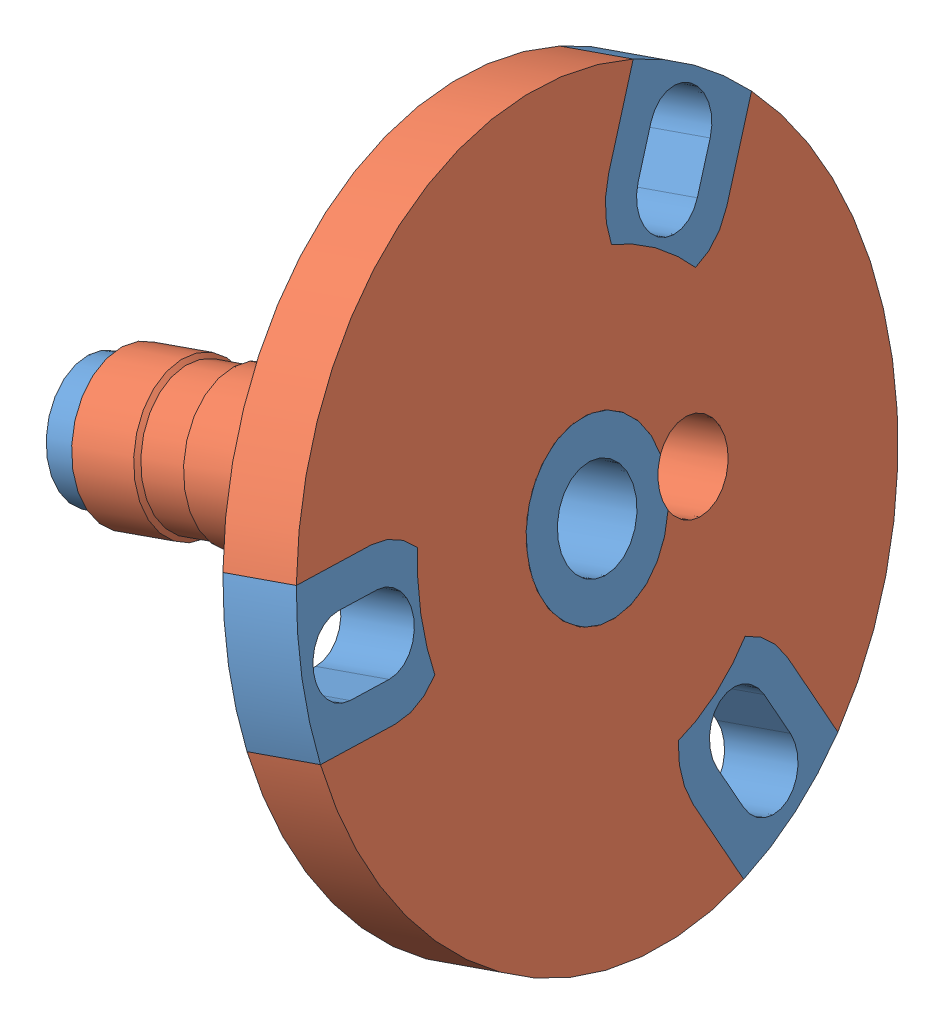
SolidWorks assembly Needle Holder Assembly, configuration Default. Lengths in mm.
Overall size (40.69 54.24 49.24).
2 component instances, 2 part files, 2 mates.
Components (placement in the parent):
- NeedleMountBottom_Heated_Rev3_Conductive-1: NeedleMountBottom_Heated_Rev3_Conductive [Default] at (-31.0476 22.1883 -11.3266) x (0.266536 -0.959645 0.089661) z (0.089661 0.11731 0.98904) size (41.78 27.15 36.24)
- NeedleMountBottom_Heated_Rev3_Standard-7: NeedleMountBottom_Heated_Rev3_Standard [Default] at (-31.0476 22.1883 -11.3266) x (0.266536 -0.959645 0.089661) z (0.089661 0.11731 0.98904) size (44.6 25.22 42.58)
Mates (geometry in assembly coordinates):
- Coincident5: coincident aligned: plane of NeedleMountBottom_Heated_Rev3_Conductive-1 through (-31.0476 22.1883 -11.3266) normal (0.959645 0.255576 -0.11731); plane of NeedleMountBottom_Heated_Rev3_Standard-7 through (-31.0476 22.1883 -11.3266) normal (0.959645 0.255576 -0.11731)
- Concentric1: concentric aligned: circle of NeedleMountBottom_Heated_Rev3_Conductive-1; circle of NeedleMountBottom_Heated_Rev3_Standard-7
